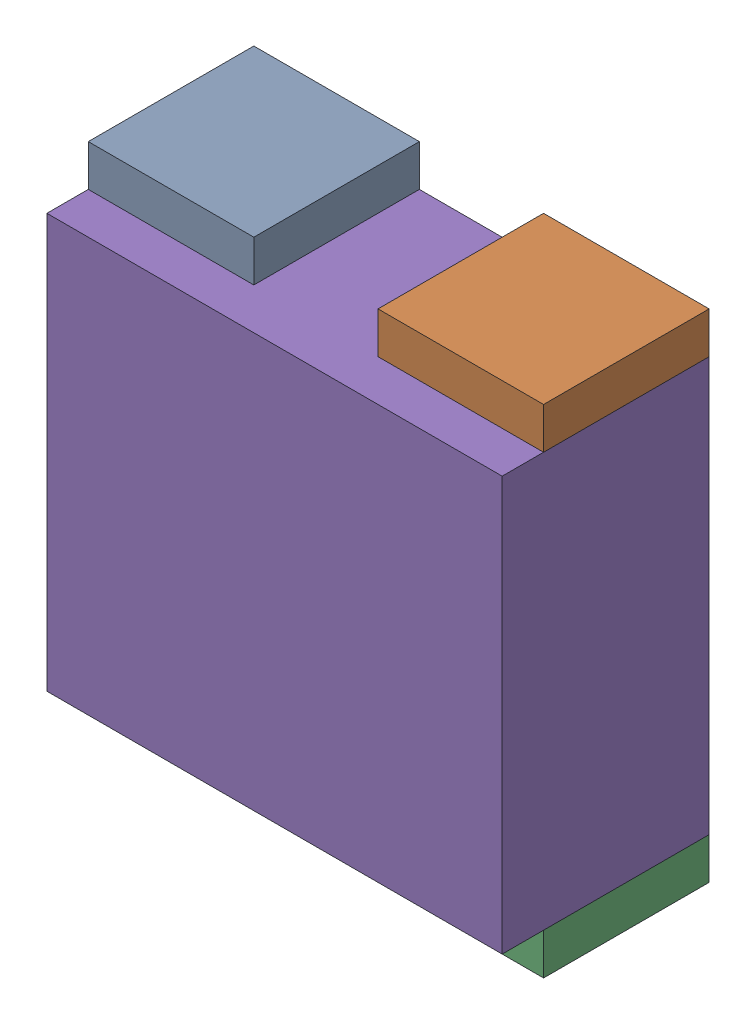
SolidWorks assembly RN23, configuration Default. Lengths in mm.
Overall size (1.1 1.2 0.5).
10 component instances, 2 part files, 0 mates.
Components (placement in the parent):
- 810157616-1: 810157616 [Default] at (126.5499 79.15 0) size (0.4 0.1 0.4)
  - Extruded_12-1: Extruded_12 [Default] at origin size (0.4 0.1 0.4)
- 810157616-2: 810157616 [Default] at (127.2499 79.15 0) size (0.4 0.1 0.4)
  - Extruded_12-1: Extruded_12 [Default] at origin size (0.4 0.1 0.4)
- 810157616-3: 810157616 [Default] at (127.2499 78.05 0) size (0.4 0.1 0.4)
  - Extruded_12-1: Extruded_12 [Default] at origin size (0.4 0.1 0.4)
- 810157616-4: 810157616 [Default] at (126.5499 78.05 0) size (0.4 0.1 0.4)
  - Extruded_12-1: Extruded_12 [Default] at origin size (0.4 0.1 0.4)
- 810156720-1: 810156720 [Default] at (126.8999 78.6 0) size (1.1 1 0.5)
  - Extruded_13-1: Extruded_13 [Default] at origin size (1.1 1 0.5)
